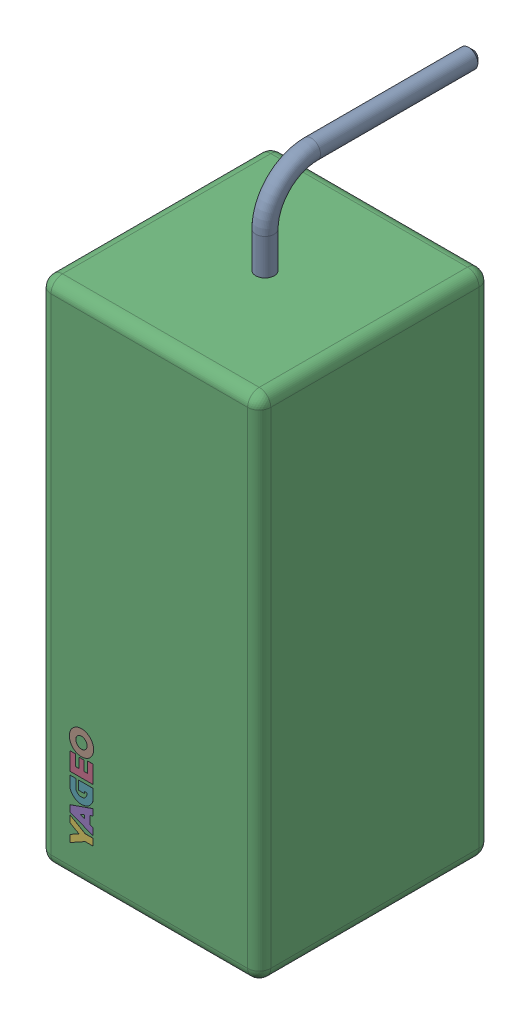
SolidWorks assembly R8.step, configuration Default. Lengths in mm.
Overall size (9.5 29.91 14).
4 component instances, 3 part files, 0 mates.
Components (placement in the parent):
- Res_Yageo_SQP500JB-1R2_eec.step-1: Res_Yageo_SQP500JB-1R2_eec.step [Default] at (85.217 60.452 0) x (0 1 0) z (0 0 1) size (29.91 9.5 14)
  - 1-6.step-1: 1-6.step [Default] at origin size (29.91 0.8 9.4)
  - 2-7.step-1: 2-7.step [Default] at origin size (22 9.5 10)
  - Yageo_Logo.step-1: Yageo_Logo.step [Default] at (-8.1443 3.6121 9.991) size (4.52 1.05 0.01)
